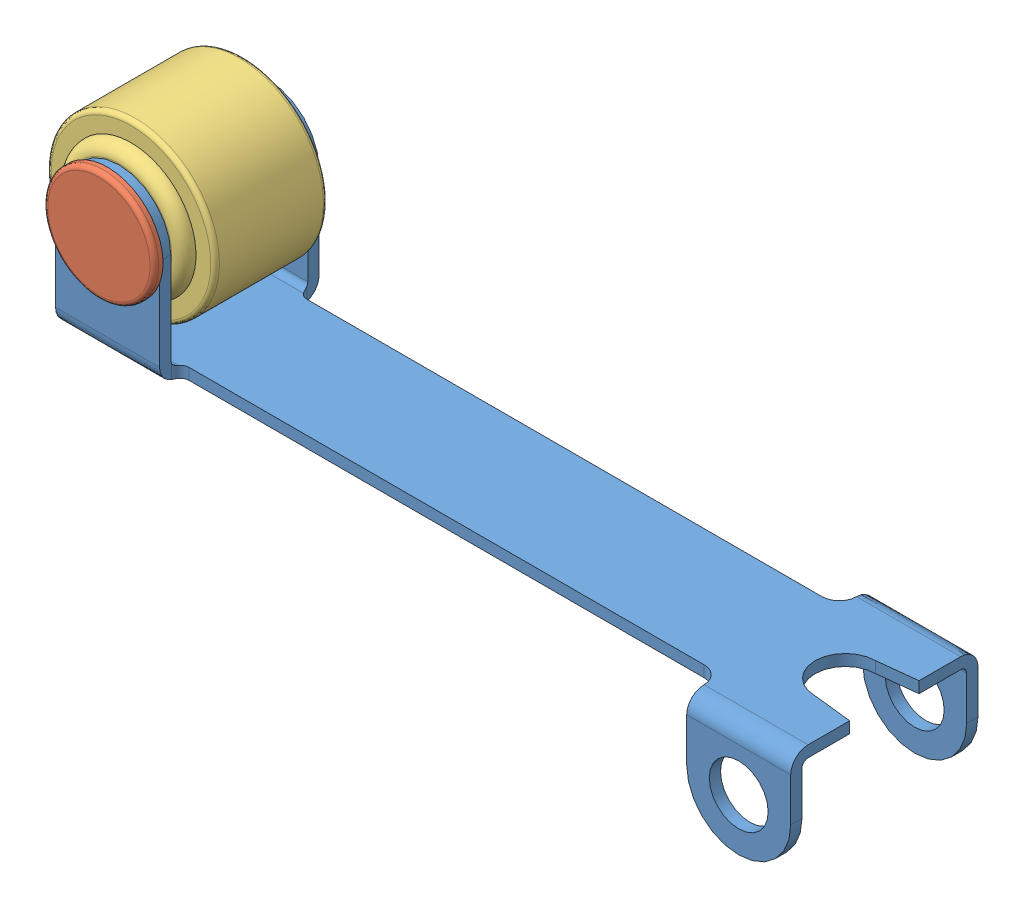
SolidWorks assembly Haste_assembly, configuration Default. Lengths in mm.
Overall size (22.52 8.5 5.4).
3 component instances, 3 part files, 4 mates.
Components (placement in the parent):
- haste-1: haste [Default] at (-0.8107 -0.671 0.8837) size (21.6 7.58 5.4)
- pino_haste-1: pino_haste [Default] at (-10.1107 2.3165 0.8837) size (3.2 3.2 5.25)
- roda-1: roda [Default] at (-10.1107 2.3165 0.8837) size (4.85 4.85 3.95)
Mates (geometry in assembly coordinates):
- Concentric1: concentric anti-aligned: cylinder of haste-1 through (-10.1107 2.3165 -1.8163) axis (0 0 1) radius 0.75; cylinder of pino_haste-1 through (-10.1107 2.3165 11.0039) axis (0 0 -1) radius 0.75
- Concentric2: concentric anti-aligned: cylinder of pino_haste-1 through (-10.1107 2.3165 3.1837) axis (0 0 -1) radius 0.75; cylinder of roda-1 through (-10.1107 2.3165 -1.0913) axis (0 0 1) radius 0.75
- Coincident1: coincident anti-aligned: plane of haste-1 through (-11.6107 3.8165 2.8587) normal (0 0 -1); plane of roda-1 through (-10.1107 2.3165 2.8587) normal (0 0 1)
- Coincident2: coincident anti-aligned: plane of haste-1 through (-11.6107 -0.5085 3.1837) normal (0 0 1); plane of pino_haste-1 through (-10.1107 2.3165 3.1837) normal (0 0 -1)
